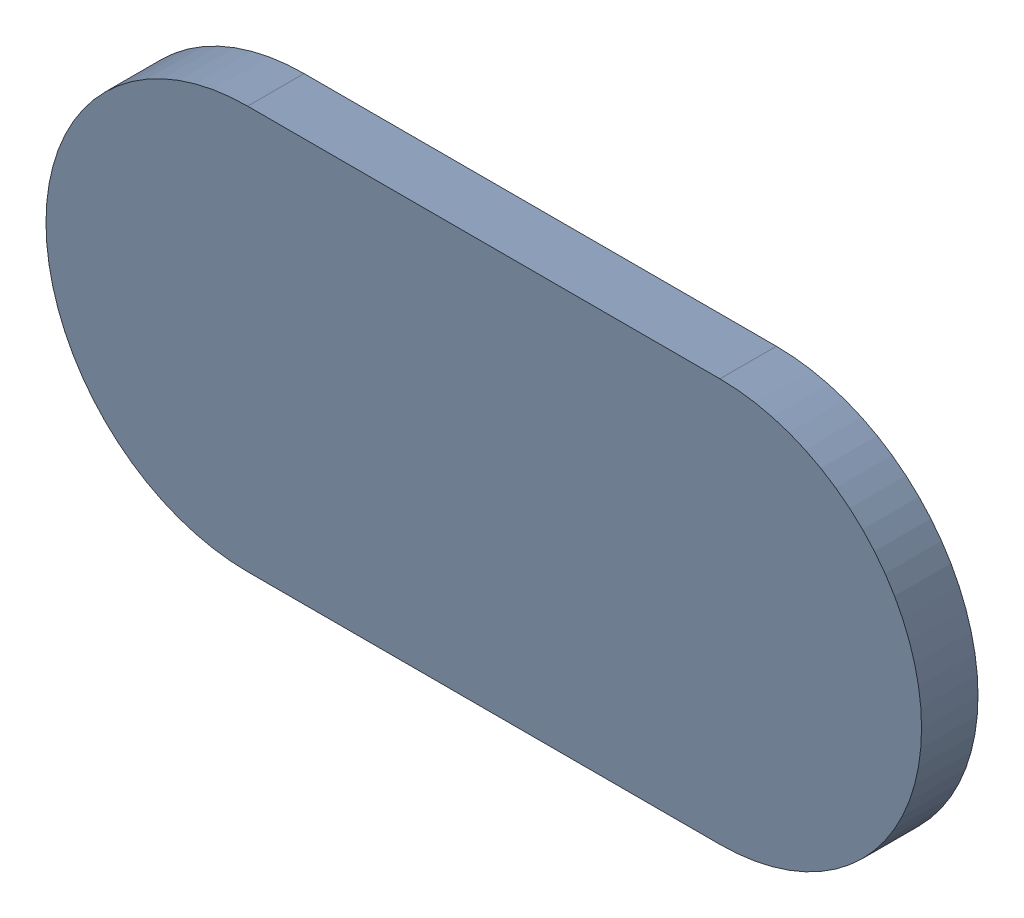
SolidWorks assembly Track (18.605mm,57mm)(18.902mm,57mm) on Top Layer, configuration Predeterminado. Lengths in mm.
Overall size (0.55 0.25 0.04).
2 component instances, 1 part files, 0 mates.
Components (placement in the parent):
- Track (18.605mm,57mm)(18.902mm,57mm) on Top Layer-1-1: Track (18.605mm,57mm)(18.902mm,57mm) on Top Layer-1 [Predeterminado] at (-68.317 -44.187 -0.0457) size (0.55 0.25 0.04)
  - Track (18.605mm,57mm)(18.902mm,57mm) on Top Layer-Part-1-1: Track (18.605mm,57mm)(18.902mm,57mm) on Top Layer-Part-1 [Predeterminado] at origin size (0.55 0.25 0.04)
